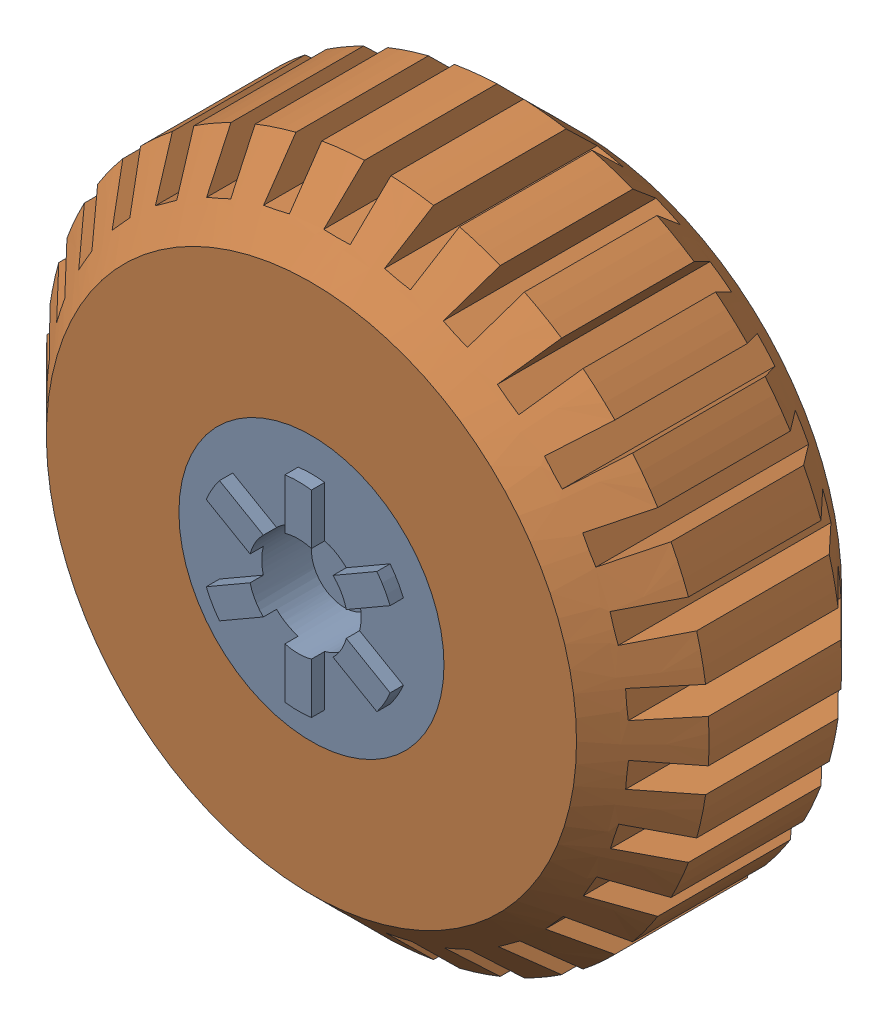
SolidWorks assembly jeep tyre Assem, configuration Default. Lengths in mm.
Overall size (100 99.92 42).
2 component instances, 2 part files, 4 mates.
Components (placement in the parent):
- jeep rim..-1: jeep rim.. [Default] at (91.1979 -15.8208 -44.1614) size (40 40 42)
- jeep tyre 1-1: jeep tyre 1 [Default] at (90.3672 -15.8208 -44.1614) size (100 99.92 40)
Mates (geometry in assembly coordinates):
- Coincident1: coincident: plane of jeep rim-1 through (91.1979 -15.8208 -14.1614) normal (0 0 1); plane of jeep tyre..-1 through (91.1979 -15.8208 -14.1614) normal (0 0 1)
- Concentric1: concentric: cylinder of jeep rim-1 through (91.1979 -15.8208 -14.1614) axis (0 0 -1) radius 20; cylinder of jeep tyre..-1 through (91.1979 -15.8208 -14.1614) axis (0 0 -1) radius 20
- Coincident2: coincident: plane of jeep rim-1 through (91.1979 -15.8208 -14.1614) normal (0 0 1); plane of jeep tyre..-1 through (91.1979 -15.8208 -14.1614) normal (0 0 1)
- Coincident3: coincident: plane of jeep rim..-1 through (91.1979 -15.8208 -4.1614) normal (0 0 1); plane of jeep tyre..-1 through (91.1979 -15.8208 -4.1614) normal (0 0 1)
